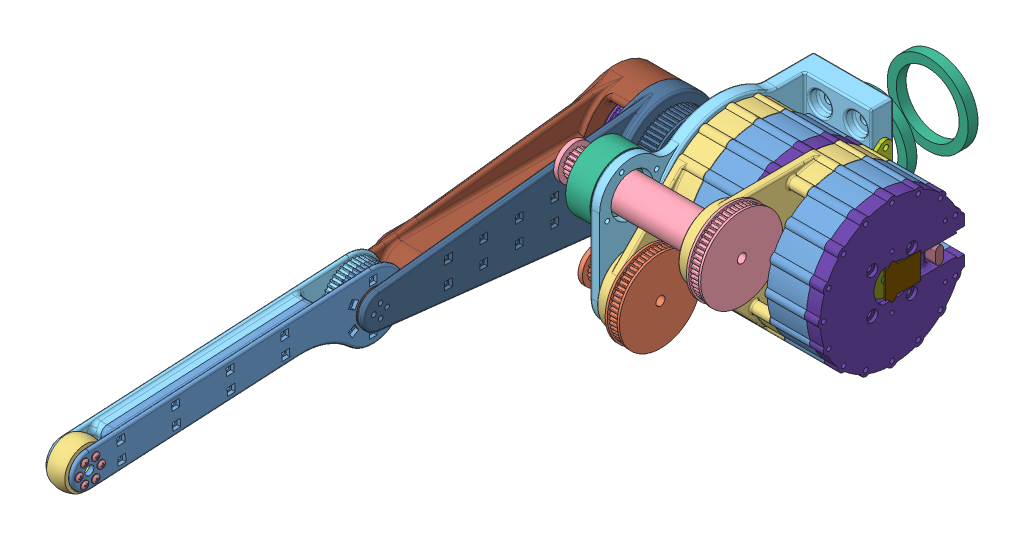
SolidWorks assembly Arm Draft Two, configuration Default. Lengths in mm.
Overall size (205.99 175.6 559.91).
64 component instances, 28 part files, 55 mates.
Components (placement in the parent):
- 0 Dimensions-1: 0 Dimensions [Default] at origin size (152.4 91.19 480.53)
- Lower_Extremedy-1: Lower_Extremedy [Default] at (-127 0 201) x (0 0 -1) z (0 -1 0) size (242.89 23.99 47.62)
  - Assem1^Lower_Extremedy-1: Assem1^Lower_Extremedy [Default] at origin size (239.71 9.67 47.62) (virtual)
    - Part2^Assem1_Lower_Extremedy-1: Part2^Assem1_Lower_Extremedy [Default] at origin size (239.71 9.67 47.62) (virtual)
    - LowerExtremedyDriven 3htd-1: LowerExtremedyDriven 3htd [Default] at origin size (43.16 13 43.07) (hidden)
    - Side_Plate_Lower-1: Side_Plate_Lower [Default] at (0 8.0875 0) size (239.71 15.88 47.62) (hidden)
  - Bearing 15_24_5mm-1: Bearing 15_24_5mm [Default] at (0 7.175 0) size (24 5 24)
  - Bearing 15_24_5mm-2: Bearing 15_24_5mm [Default] at (0 -7.175 0) x (1 0 0) z (0 0 -1) size (24 5 24)
  - foot-1: foot [Default] at (-203.2 0 0) size (31.75 13 31.75)
  - .375 plastight 92295A101_PHILLIPS THREAD-FORMING SCREW FOR PLASTIC-49: .375 plastight 92295A101_PHILLIPS THREAD-FORMING SCREW FOR PLASTIC [92295A101] at (-211.1375 -4.9125 0) x (1 0 0) z (0 -1 0) size (5.56 5.56 13.46)
  - .375 plastight 92295A101_PHILLIPS THREAD-FORMING SCREW FOR PLASTIC-50: .375 plastight 92295A101_PHILLIPS THREAD-FORMING SCREW FOR PLASTIC [92295A101] at (-207.1688 -4.9125 6.8741) x (0.5 0 -0.866025) z (0 -1 0) size (5.56 5.56 13.46)
  - .375 plastight 92295A101_PHILLIPS THREAD-FORMING SCREW FOR PLASTIC-51: .375 plastight 92295A101_PHILLIPS THREAD-FORMING SCREW FOR PLASTIC [92295A101] at (-199.2312 -4.9125 6.8741) x (-0.5 0 -0.866025) z (0 -1 0) size (5.56 5.56 13.46)
  - .375 plastight 92295A101_PHILLIPS THREAD-FORMING SCREW FOR PLASTIC-52: .375 plastight 92295A101_PHILLIPS THREAD-FORMING SCREW FOR PLASTIC [92295A101] at (-195.2625 -4.9125 0) x (-1 0 0) z (0 -1 0) size (5.56 5.56 13.46)
  - .375 plastight 92295A101_PHILLIPS THREAD-FORMING SCREW FOR PLASTIC-53: .375 plastight 92295A101_PHILLIPS THREAD-FORMING SCREW FOR PLASTIC [92295A101] at (-199.2312 -4.9125 -6.8741) x (-0.5 0 0.866025) z (0 -1 0) size (5.56 5.56 13.46)
  - .375 plastight 92295A101_PHILLIPS THREAD-FORMING SCREW FOR PLASTIC-54: .375 plastight 92295A101_PHILLIPS THREAD-FORMING SCREW FOR PLASTIC [92295A101] at (-207.1688 -4.9125 -6.8741) x (0.5 0 0.866025) z (0 -1 0) size (5.56 5.56 13.46)
  - .375 plastight 92295A101_PHILLIPS THREAD-FORMING SCREW FOR PLASTIC-55: .375 plastight 92295A101_PHILLIPS THREAD-FORMING SCREW FOR PLASTIC [92295A101] at (-211.1375 4.9125 0) x (1 0 0) z (0 1 0) size (5.56 5.56 13.46)
  - .375 plastight 92295A101_PHILLIPS THREAD-FORMING SCREW FOR PLASTIC-56: .375 plastight 92295A101_PHILLIPS THREAD-FORMING SCREW FOR PLASTIC [92295A101] at (-207.1688 4.9125 6.8741) x (-0.5 0 0.866025) z (0 1 0) size (5.56 5.56 13.46)
  - .375 plastight 92295A101_PHILLIPS THREAD-FORMING SCREW FOR PLASTIC-57: .375 plastight 92295A101_PHILLIPS THREAD-FORMING SCREW FOR PLASTIC [92295A101] at (-199.2312 4.9125 6.8741) x (0.5 0 0.866025) z (0 1 0) size (5.56 5.56 13.46)
  - .375 plastight 92295A101_PHILLIPS THREAD-FORMING SCREW FOR PLASTIC-58: .375 plastight 92295A101_PHILLIPS THREAD-FORMING SCREW FOR PLASTIC [92295A101] at (-195.2625 4.9125 0) x (-1 0 0) z (0 1 0) size (5.56 5.56 13.46)
  - .375 plastight 92295A101_PHILLIPS THREAD-FORMING SCREW FOR PLASTIC-59: .375 plastight 92295A101_PHILLIPS THREAD-FORMING SCREW FOR PLASTIC [92295A101] at (-199.2312 4.9125 -6.8741) x (0.5 0 -0.866025) z (0 1 0) size (5.56 5.56 13.46)
  - .375 plastight 92295A101_PHILLIPS THREAD-FORMING SCREW FOR PLASTIC-60: .375 plastight 92295A101_PHILLIPS THREAD-FORMING SCREW FOR PLASTIC [92295A101] at (-207.1688 4.9125 -6.8741) x (-0.5 0 -0.866025) z (0 1 0) size (5.56 5.56 13.46)
  - left side mirrot-1: left side mirrot [Default] at origin size (239.71 9.67 47.62)
- UpperPivotAssem-1: UpperPivotAssem [Default] at (-127 0 0) size (70.97 73.04 249.05)
  - Bearing 45_58_7mm-1: Bearing 45_58_7mm [Default] at (10.5875 0 0) x (0 0 -1) z (1 0 0) size (58 58 7)
  - Bearing 25_37_7mm-1: Bearing 25_37_7mm [Default] at (45.8625 0 0) size (7 37 37)
  - Bearing 25_37_7mm-2: Bearing 25_37_7mm [Default] at (-14.9375 0 0) size (7 37 37)
  - 60T 40T htd3mm - Copy-1: 60T 40T htd3mm - Copy [Default] at (44.45 0 0) x (0 0 -1) z (0 1 0) size (58.88 60.62 58.88)
  - Part2-1: Part2 [Default] at (-7.4688 0 0) x (0 0 -1) z (0 -1 0) size (31.55 7.94 31.55)
  - Bearing 25_37_7mm-3: Bearing 25_37_7mm [Default] at origin size (7 37 37)
  - UpperExtremedyDriven 3htd-1: UpperExtremedyDriven 3htd [Default] at (26.9875 0 0) x (0 0 1) z (0 1 0) size (249.05 27.99 71.22)
  - outside shield-support-2: outside shield-support [Default] at (-10.16 0 0) size (25.52 73.04 247.46)
  - pivot-1: pivot [Default] at (0 0 201) x (0 -1 0) z (0 0 1) size (15 20.63 15)
- Motor Assem-3: Motor Assem [Default] at (-29.0475 0 0) x (0 1 0) z (0 0 1) size (129.63 57.83 129.63)
  - 9225 160kv-1: 9225 160kv [Default] at (0 -18.055 0) x (0.707107 0 0.707107) z (-0.707107 0 0.707107) size (91.66 44.53 91.66)
  - 15 tooth htd 3mm pulley-1: 15 tooth htd 3mm pulley [Default] at (0 21.7525 0) x (0.707107 0 0.707107) z (-0.707107 0 0.707107) size (39.69 19.3 39.69)
  - Encoder Magnet-1: Encoder Magnet [Default] at (0 -19.6425 0) size (6.35 3.17 6.35)
  - Bearing 15_24_5mm-1: Bearing 15_24_5mm [Default] at (0 30.9275 0) size (24 5 24)
  - Magnut hex puck-1: Magnut hex puck [Default] at (0 -18.055 0) x (0.707107 0 0.707107) z (-0.707107 0 0.707107) size (22.91 4.76 22.91)
  - Motor Bracket Base-1: Motor Bracket Base [Default] at origin size (105.95 14.23 104.77)
  - encoder final board-1: encoder final board [Default] at (0 -23.0237 -0.3766) x (0 0 -1) z (1 0 0) size (25.25 2.95 25)
  - Part1-1: Part1 [Default] at origin size (105.95 28.25 104.77)
- Short 60T 20T htd3mm-2: Short 60T 20T htd3mm [Default] at (-50.8 -27.7331 66.9535) x (0 1 0) z (0 0 1) size (58.88 46.51 58.88)
- Bearing 25_37_7mm-2: Bearing 25_37_7mm [Default] at (-60.6575 -27.7331 66.9535) x (1 0 0) z (0 -0.366349 0.930478) size (7 37 37)
- outrigger_pulley_support-1: outrigger_pulley_support [Default] at (-43.1725 0 0) x (0 0.707107 -0.707107) z (-1 0 0) size (142.11 106.22 23.03)
- Motor Assem-1: Motor Assem [Default] at (29.182 0 0) x (0 1 0) z (0 0 1) size (129.63 57.83 129.63)
  - 9225 160kv-1: 9225 160kv [Default] at (0 -18.055 0) x (0.707107 0 0.707107) z (-0.707107 0 0.707107) size (91.66 44.53 91.66)
  - 15 tooth htd 3mm pulley-1: 15 tooth htd 3mm pulley [Default] at (0 21.7525 0) x (0.707107 0 0.707107) z (-0.707107 0 0.707107) size (39.69 19.3 39.69)
  - Encoder Magnet-1: Encoder Magnet [Default] at (0 -19.6425 0) size (6.35 3.17 6.35)
  - Bearing 15_24_5mm-1: Bearing 15_24_5mm [Default] at (0 30.9275 0) size (24 5 24)
  - Magnut hex puck-1: Magnut hex puck [Default] at (0 -18.055 0) x (0.707107 0 0.707107) z (-0.707107 0 0.707107) size (22.91 4.76 22.91)
  - Motor Bracket Base-1: Motor Bracket Base [Default] at origin size (105.95 14.23 104.77)
  - encoder final board-1: encoder final board [Default] at (0 -23.0237 -0.3766) x (0 0 -1) z (1 0 0) size (25.25 2.95 25)
  - Part1-1: Part1 [Default] at origin size (105.95 28.25 104.77)
- Long 60T 20T htd3mm-2: Long 60T 20T htd3mm [Default] at (7.4295 27.7331 66.9535) x (0 -1 0) z (0 0 -1) size (58.88 122.2 58.88)
- Bearing 25_37_7mm-1: Bearing 25_37_7mm [Default] at (-2.428 27.7331 66.9535) x (1 0 0) z (0 -0.19278 0.981242) size (7 37 37)
- outrigger_pulley_support-2: outrigger_pulley_support [Default] at (15.057 0 0) x (0 0 -1) z (-1 0 0) size (142.11 106.22 23.03)
- 0 Dimensions-3: 0 Dimensions [Default] at origin size (152.4 91.19 480.53)
- Shoulder Master Bracket test shaft-3: Shoulder Master Bracket test shaft [Default] at (-15.725 0 0) x (-1 0 0) z (0 1 0) size (129.71 160.07 107.95)
- Bearing 45_58_7mm-3: Bearing 45_58_7mm [Default] at (-44.45 0 -126.675) x (0.648399 0.7613 0) z (0 0 1) size (58 58 7)
- Bearing 45_58_7mm-4: Bearing 45_58_7mm [Default] at (-44.45 0 -82.875) x (-0.541916 -0.840432 0) z (0 0 1) size (58 58 7)
- Bearing 25_37_7mm-3: Bearing 25_37_7mm [Default] at (-69.375 -27.7331 66.9535) x (1 0 0) z (0 -0.140315 0.990107) size (7 37 37)
- Bearing 25_37_7mm-4: Bearing 25_37_7mm [Default] at (-86.8375 27.7331 66.9535) x (1 0 0) z (0 0.096413 0.995341) size (7 37 37)
- support-1: support [Default] at (-72.875 27.7331 66.9535) size (17.46 46.52 46.52)
- Part1^Arm Draft Two-1: Part1^Arm Draft Two [Default] at origin size (9.67 47.62 14.9) (virtual)
Mates (geometry in assembly coordinates):
- Coincident5: coincident aligned: line of 0 Dimensions-1 through (0 50.8 -152.4) axis (0 0 1); line of Motor Assem-1 through (0 63.6157 -7.1371) axis (0 0 1)
- Coincident4: coincident aligned: plane of Motor Assem-1 through (29.182 0 0) normal (0 0 1)
- Coincident8: coordinate: point of assembly; point of 0 Dimensions-1; point of assembly
- Coincident9: coincident aligned: line of 0 Dimensions-1 through (0 50.8 -152.4) axis (0 0 1); line of Motor Assem-3 through (0 63.6157 -65.3666) axis (0 0 1)
- Coincident10: coincident aligned: plane of Motor Assem-3 through (-29.0475 0 0) normal (0 1 0)
- Symmetric1: symmetric anti-aligned: plane of 0 Dimensions-1 through (0 0 0) normal (1 0 0); plane of Motor Assem-1 through (31.5724 0 0) normal (-1 0 0); plane of Motor Assem-3 through (-31.5724 0 0) normal (-1 0 0)
- Coincident16: coincident aligned: plane of Motor Assem-1/15 tooth htd 3mm pulley-1 through (7.4295 0 0) normal (-1 0 0); plane of Long 60T 20T htd3mm-2 through (7.4295 27.7331 66.9535) normal (-1 0 0)
- Coincident17: coincident aligned: plane of Motor Assem-3/15 tooth htd 3mm pulley-1 through (-50.8 0 0) normal (-1 0 0); plane of Short 60T 20T htd3mm-2 through (-50.8 -27.7331 66.9535) normal (-1 0 0)
- Coincident18: coincident: point of 0 Dimensions-1; line of Short 60T 20T htd3mm-2 through (-85.7332 -27.7331 66.9535) axis (1 0 0)
- Coincident19: coincident: point of 0 Dimensions-1; line of Long 60T 20T htd3mm-2 through (-27.5037 27.7331 66.9535) axis (1 0 0)
- Parallel2: parallel anti-aligned: plane of Long 60T 20T htd3mm-2 through (7.4295 27.7331 66.9535) normal (0 0 -1)
- Parallel3: parallel aligned: plane of Short 60T 20T htd3mm-2 through (-50.8 -27.7331 66.9535) normal (0 0 1)
- Concentric8: concentric anti-aligned: line of 0 Dimensions-1 through (0 50.8 -152.4) axis (0 0 1); cylinder of UpperPivotAssem-1/Bearing 45_58_7mm-1 through (-112.9125 0 0) axis (-1 0 0) radius 22.5
- Concentric9: concentric anti-aligned: line of 0 Dimensions-1 through (0 50.8 -152.4) axis (0 0 1); cylinder of UpperPivotAssem-1/Bearing 25_37_7mm-1 through (-77.6375 0 0) axis (-1 0 0) radius 12.5
- Concentric10: concentric anti-aligned: line of 0 Dimensions-1 through (0 50.8 -152.4) axis (0 0 1); cylinder of UpperPivotAssem-1/Bearing 25_37_7mm-2 through (-138.4375 0 0) axis (-1 0 0) radius 18.5
- Coincident32: coincident aligned: line of 0 Dimensions-1 through (0 50.8 -152.4) axis (0 0 1); line of UpperPivotAssem-1/60T 40T htd3mm - Copy-1 through (-117.4832 0 0) axis (1 0 0)
- Coincident33: coincident: unknown of Assem1^Arm Draft Two-1/60T 40T htd3mm - Copy-1; plane of assembly through (0 0 0) normal (0 0 1)
- Coincident34: coincident aligned: plane of Short 60T 20T htd3mm-2 through (-82.55 -27.7331 66.9535) normal (-1 0 0); plane of UpperPivotAssem-1/60T 40T htd3mm - Copy-1 through (-82.55 0 0) normal (-1 0 0)
- Coincident36: coincident: line of 0 Dimensions-1 through (-127 0 404.2) axis (0 0 -1); plane of UpperPivotAssem-1/60T 40T htd3mm - Copy-1 through (-127 0 0) normal (-1 0 0)
- Concentric11: concentric anti-aligned: cylinder of UpperPivotAssem-1/Part2-1 through (-130.5 0 0) axis (-1 0 0) radius 12.6; line of 0 Dimensions-1 through (0 50.8 -152.4) axis (0 0 1)
- Concentric13: concentric anti-aligned: line of 0 Dimensions-1 through (0 50.8 -152.4) axis (0 0 1); cylinder of UpperPivotAssem-1/Bearing 25_37_7mm-3 through (-123.5 0 0) axis (-1 0 0) radius 12.5
- Coincident43: coincident anti-aligned: line of 0 Dimensions-1 through (-152.4 0 201) axis (1 0 0); line of Lower_Extremedy-1 through (-113.803 0 201) axis (-1 0 0)
- Coincident45: coincident anti-aligned: plane of UpperPivotAssem-1/60T 40T htd3mm - Copy-1 through (-127 0 0) normal (-1 0 0); plane of Lower_Extremedy-1/LowerExtremedyDriven 3htd-1 through (-127 0 203.2) normal (1 0 0)
- Coincident46: coincident anti-aligned: plane of Lower_Extremedy-1 through (-127 0 201) normal (0 -1 0)
- Coincident47: coincident anti-aligned: plane of UpperPivotAssem-1/60T 40T htd3mm - Copy-1 through (-127 0 0) normal (-1 0 0); plane of Lower_Extremedy-1 through (-127 0 201) normal (1 0 0)
- Coincident55: coincident aligned: plane of UpperPivotAssem-1 through (-127 0 0) normal (0 1 0)
- Concentric15: concentric anti-aligned: line of 0 Dimensions-1 through (0 50.8 -152.4) axis (0 0 1); cylinder of UpperPivotAssem-1/UpperExtremedyDriven 3htd-1 through (-91.925 0 0) axis (-1 0 0) radius 23.8852
- Parallel7: parallel: plane of assembly through (0 0 0) normal (0 1 0); plane of UpperPivotAssem-1/UpperExtremedyDriven 3htd-1 through (-100.0125 0 0) normal (0 1 0)
- Coincident62: coincident anti-aligned: plane of Long 60T 20T htd3mm-2 through (-100.0125 27.7331 66.9535) normal (-1 0 0); plane of UpperPivotAssem-1/UpperExtremedyDriven 3htd-1 through (-100.0125 0 0) normal (1 0 0)
- Coincident64: coincident anti-aligned: line of Motor Assem-3 through (0 63.6157 -65.3666) axis (0 0 1); line of outrigger_pulley_support-1 through (0 22.979 -42.128) axis (0 0 -1)
- Coincident66: coincident anti-aligned: line of Motor Assem-1 through (0 63.6157 -7.1371) axis (0 0 1); line of outrigger_pulley_support-2 through (16.1015 0 0) axis (-1 0 0)
- Concentric18: concentric aligned: cylinder of Long 60T 20T htd3mm-2 through (2.342 27.7331 66.9535) axis (1 0 0) radius 12.5; cylinder of outrigger_pulley_support-2 through (-183.9571 27.7331 66.9535) axis (1 0 0) radius 18.5
- Concentric19: concentric anti-aligned: cylinder of outrigger_pulley_support-2 through (-183.9571 27.7331 66.9535) axis (1 0 0) radius 18.5; cylinder of Bearing 25_37_7mm-1 through (1.072 27.7331 66.9535) axis (-1 0 0) radius 18.5
- Coincident68: coincident anti-aligned: plane of Long 60T 20T htd3mm-2 through (1.072 41.8206 66.9535) normal (-1 0 0); plane of Bearing 25_37_7mm-1 through (1.072 27.7331 66.9535) normal (1 0 0)
- Concentric20: concentric anti-aligned: cylinder of outrigger_pulley_support-1 through (-242.1866 -27.7331 66.9535) axis (1 0 0) radius 18.5; cylinder of Bearing 25_37_7mm-2 through (-57.1575 -27.7331 66.9535) axis (-1 0 0) radius 12.5
- Coincident69: coincident anti-aligned: plane of Short 60T 20T htd3mm-2 through (-57.1575 -41.8206 66.9535) normal (-1 0 0); circle of Bearing 25_37_7mm-2
- Concentric1: concentric: line of 0 Dimensions-3 through (0 50.8 -152.4) axis (0 0 1); cylinder of Shoulder Master Bracket test shaft-3 through (-180.7928 0 0) axis (1 0 0) radius 12.5
- Concentric3: concentric aligned: line of 0 Dimensions-3 through (-44.45 0 0) axis (0 0 -1); cylinder of Bearing 45_58_7mm-4 through (-44.45 0 -79.375) axis (0 0 -1) radius 22.5
- Concentric2: concentric aligned: cylinder of Bearing 45_58_7mm-3 through (-44.45 0 -123.175) axis (0 0 -1) radius 29; cylinder of Bearing 45_58_7mm-4 through (-44.45 0 -79.375) axis (0 0 -1) radius 29
- Concentric31: concentric: line of 0 Dimensions-1 through (0 50.8 -152.4) axis (0 0 1); cylinder of Shoulder Master Bracket test shaft-3 through (-180.7928 0 0) axis (1 0 0) radius 12.5
- Coincident74: coincident anti-aligned: circle of Shoulder Master Bracket test shaft-3; plane of UpperPivotAssem-1/Bearing 25_37_7mm-1 through (-77.6375 0 0) normal (1 0 0)
- Concentric32: concentric aligned: line of 0 Dimensions-1 through (-44.45 0 0) axis (0 0 -1); cylinder of Bearing 45_58_7mm-3 through (-44.45 0 -123.175) axis (0 0 -1) radius 29
- Concentric33: concentric aligned: line of 0 Dimensions-1 through (-44.45 0 0) axis (0 0 -1); cylinder of Bearing 45_58_7mm-4 through (-44.45 0 -79.375) axis (0 0 -1) radius 29
- Distance2: distance = 9.525 mm anti-aligned: plane of Shoulder Master Bracket test shaft-3 through (-15.725 53.975 -69.85) normal (0 0 -1); plane of Bearing 45_58_7mm-4 through (-44.45 0 -79.375) normal (0 0 1)
- Distance1: distance = 50.8 mm anti-aligned: plane of Bearing 45_58_7mm-4 through (-44.45 0 -79.375) normal (0 0 1); plane of Bearing 45_58_7mm-3 through (-44.45 0 -130.175) normal (0 0 -1)
- Concentric34: concentric anti-aligned: cylinder of Short 60T 20T htd3mm-2 through (-55.8875 -27.7331 66.9535) axis (1 0 0) radius 12.5; cylinder of Bearing 25_37_7mm-3 through (-65.875 -27.7331 66.9535) axis (-1 0 0) radius 18.5
- Concentric35: concentric anti-aligned: cylinder of Long 60T 20T htd3mm-2 through (2.342 27.7331 66.9535) axis (1 0 0) radius 12.5; cylinder of Bearing 25_37_7mm-4 through (-83.3375 27.7331 66.9535) axis (-1 0 0) radius 18.5
- Coincident77: coincident aligned: plane of Shoulder Master Bracket test shaft-3 through (-72.875 53.975 -63.5) normal (-1 0 0); plane of Bearing 25_37_7mm-3 through (-72.875 -27.7331 66.9535) normal (-1 0 0)
- Distance3: distance = 3.175 mm aligned: plane of Bearing 25_37_7mm-4 through (-90.3375 27.7331 66.9535) normal (-1 0 0); plane of Long 60T 20T htd3mm-2 through (-93.5125 27.7331 66.9535) normal (-1 0 0)
- Coincident78: coincident anti-aligned: plane of Motor Assem-1/Part1-1 through (15.057 22.981 22.981) normal (-1 0 0); plane of outrigger_pulley_support-2 through (15.057 0 24.5025) normal (1 0 0)
- Coincident79: coincident anti-aligned: plane of Motor Assem-3/Part1-1 through (-43.1725 22.981 22.981) normal (-1 0 0); plane of outrigger_pulley_support-1 through (-43.1725 -17.3259 17.3259) normal (1 0 0)
- Concentric36: concentric anti-aligned: cylinder of Short 60T 20T htd3mm-2 through (-55.8875 -27.7331 66.9535) axis (1 0 0) radius 12.5; cylinder of Bearing 25_37_7mm-2 through (-57.1575 -27.7331 66.9535) axis (-1 0 0) radius 12.5
- Coincident80: coincident anti-aligned: plane of Shoulder Master Bracket test shaft-3 through (-72.875 53.975 -63.5) normal (-1 0 0); plane of support-1 through (-72.875 27.7331 66.9535) normal (1 0 0)
- Concentric37: concentric: cylinder of Long 60T 20T htd3mm-2 through (2.342 27.7331 66.9535) axis (1 0 0) radius 12.5; point of support-1
- Parallel8: parallel aligned: plane of support-1 through (-72.875 27.7331 66.9535) normal (0 1 0)
